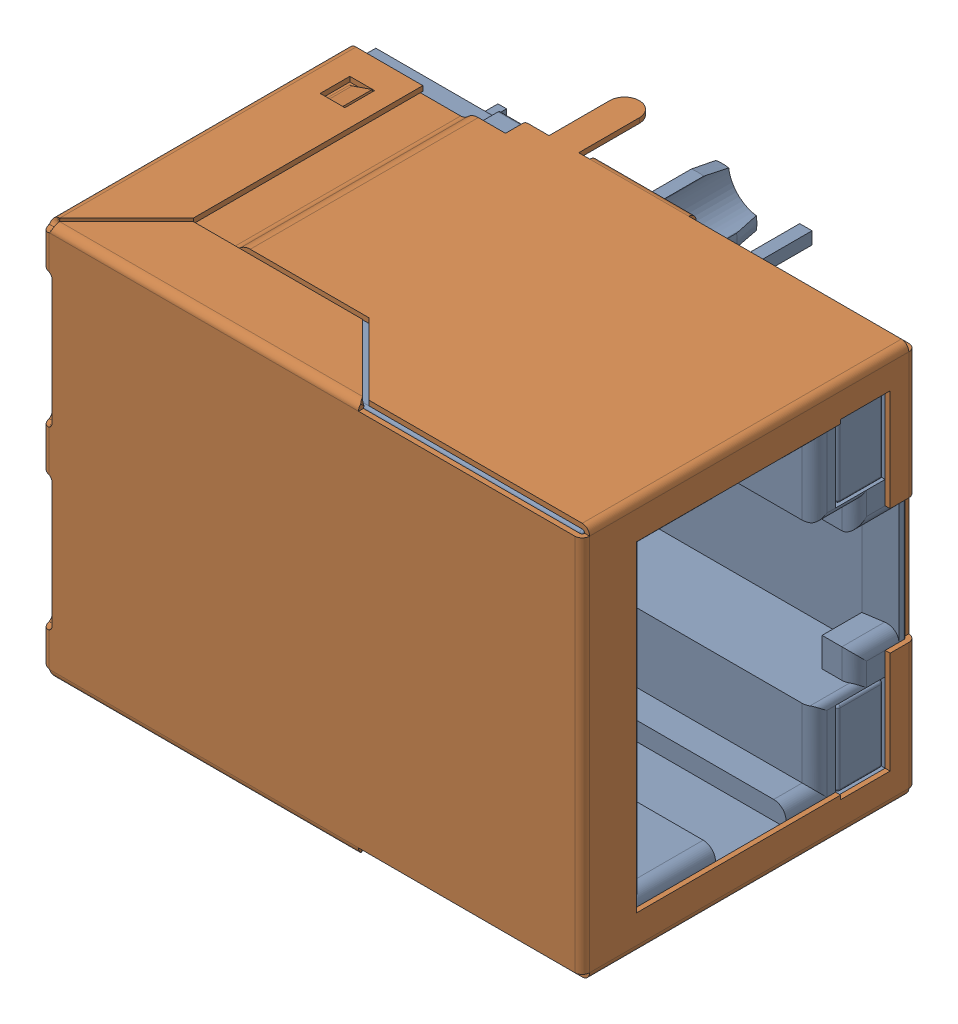
SolidWorks assembly T1, configuration Standard. Lengths in mm.
Overall size (21.84 15.88 16.55).
3 component instances, 2 part files, 0 mates.
Components (placement in the parent):
- 7499010211A-1: 7499010211A [Standard] at (24.4001 -0.1251 6.7) x (0 -1 0) z (0 0 -1) size (15.88 21.84 16.55)
  - housing-1: housing [Standard] at origin size (15.48 21.44 16.35)
  - shielding-1: shielding [Standard] at origin size (15.88 21.84 16.25)
